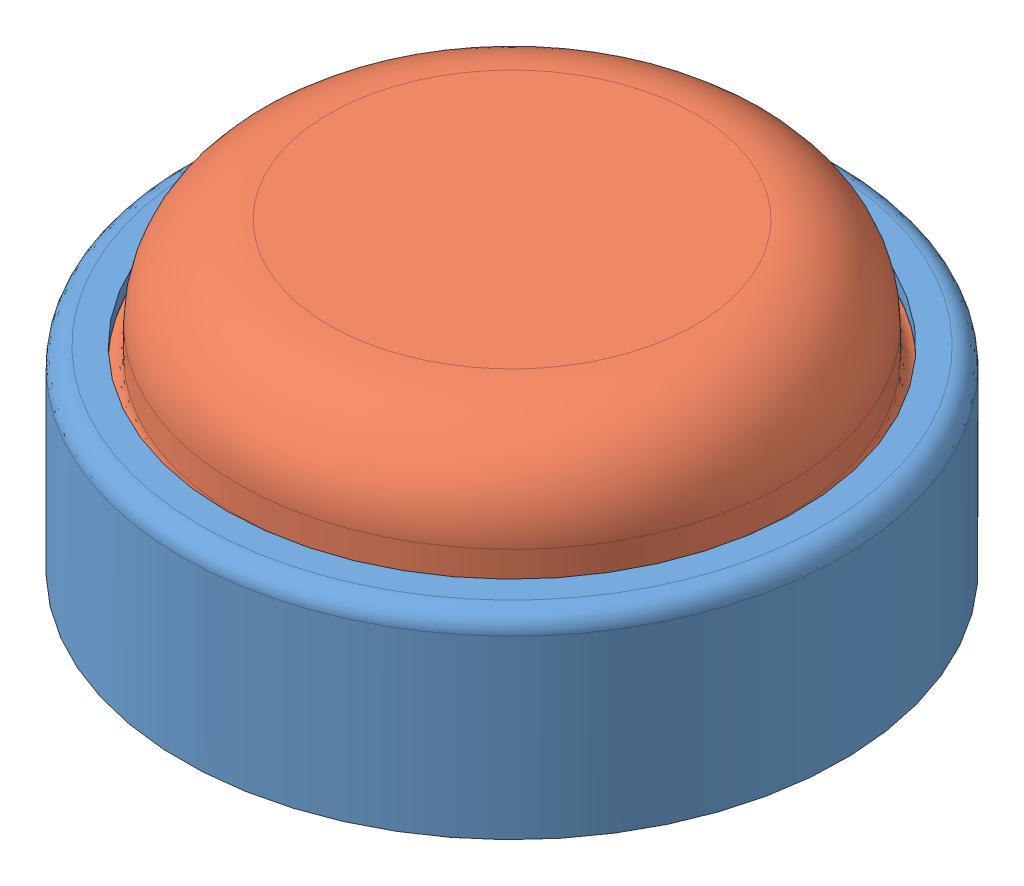
SolidWorks assembly Switch Assembly, configuration Default. Lengths in mm.
Overall size (116.31 42.19 116.31).
4 component instances, 4 part files, 6 mates.
Components (placement in the parent):
- Switch Side-1: Switch Side [Default] at origin size (91.44 26.99 91.44)
- Switch Top-1: Switch Top [Default] at (0 18.3797 0) size (87.63 22.23 87.63)
- Switch Bottom-2: Switch Bottom [Default] at (0 -4.6302 0) x (-0.765352 0 -0.643611) z (0.643611 0 -0.765352) size (82.55 15.18 82.55)
- Switch Reference-4: Switch Reference [Default] at (-0.7045 5.4663 0.0609) x (0.643611 0 -0.765352) z (0.765352 0 0.643611) size (12 9.1 12)
Mates (geometry in assembly coordinates):
- Concentric1: concentric anti-aligned: cylinder of Switch Side-1 through (0 19.05 0) axis (0 -1 0) radius 41.91; cylinder of Switch Top-1 through (0 15.2047 0) axis (0 1 0) radius 41.275
- Parallel5: parallel aligned: plane of Switch Side-1 through (2.921 19.05 -44.323) normal (0 0 1); plane of Switch Top-1 through (-2.54 18.3797 43.815) normal (0 0 1)
- Concentric3: concentric aligned: circle of Switch Side-1; circle of Switch Bottom-2
- Coincident34: coincident anti-aligned: plane of Switch Bottom-2 through (0 5.4663 0) normal (0 1 0); plane of Switch Reference-4 through (-0.7045 5.4663 0.0609) normal (0 -1 0)
- Coincident35: coincident anti-aligned: plane of Switch Bottom-2 through (8.5147 10.5463 -0.026) normal (-0.643611 0 0.765352); plane of Switch Reference-4 through (-1.4349 11.9663 -8.3929) normal (0.643611 0 -0.765352)
- Coincident37: coincident anti-aligned: plane of Switch Bottom-2 through (-1.4349 10.5463 -8.3929) normal (0.765352 0 0.643611); plane of Switch Reference-4 through (-9.1583 11.9663 0.7913) normal (-0.765352 0 -0.643611)
